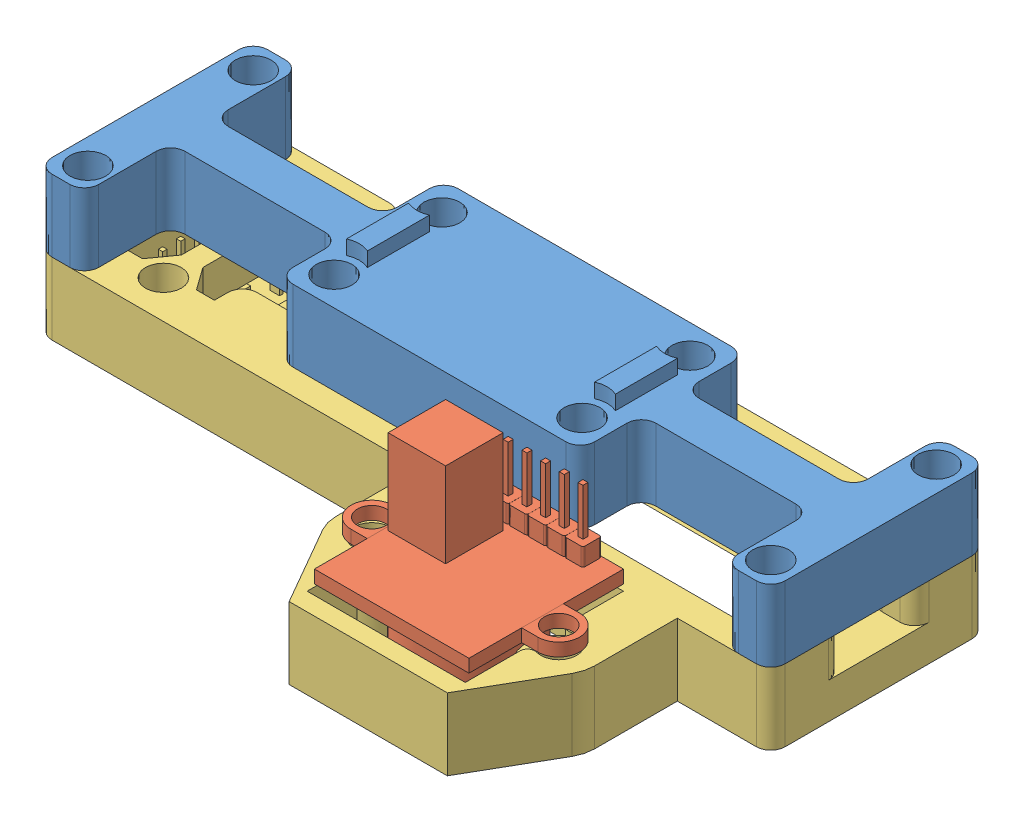
SolidWorks assembly Assem1, configuration Default. Lengths in mm.
Overall size (102 26.6 55).
3 component instances, 3 part files, 8 mates.
Components (placement in the parent):
- mount-1: mount [Default] at (-26.1725 19.4301 19.9304) size (102 12 30)
- GY-US42 ULTERASONIC madule-1: GY-US42 ULTERASONIC madule [Default] at (-25.3917 11.8438 36.0304) x (-1 0 0) z (0 0 1) size (31.8 26.6 21.5)
- cover_3-1: cover_3 [Default] at (-66.9225 -0.5699 32.1804) x (0 0 -1) z (0 1 0) size (55 102 11.3)
Mates (geometry in assembly coordinates):
- Concentric1: concentric anti-aligned: circle of mount-1; circle of cover-1
- Concentric2: concentric aligned: circle of mount-1; circle of cover_2-1
- Concentric3: concentric aligned: circle of mount-1; circle of cover_2-1
- Concentric5: concentric aligned: circle of mount-1; circle of cover_3-1
- Concentric6: concentric aligned: circle of mount-1; circle of cover_3-1
- Coincident4: coincident anti-aligned: plane of mount-1 through (-26.1725 9.4301 19.9304) normal (0 -1 0); plane of cover_3-1 through (-66.9225 9.4301 32.1804) normal (0 1 0)
- Concentric7: concentric anti-aligned: circle of GY-US42 ULTERASONIC madule-1; circle of cover_3-1
- Concentric8: concentric anti-aligned: circle of GY-US42 ULTERASONIC madule-1; circle of cover_3-1
